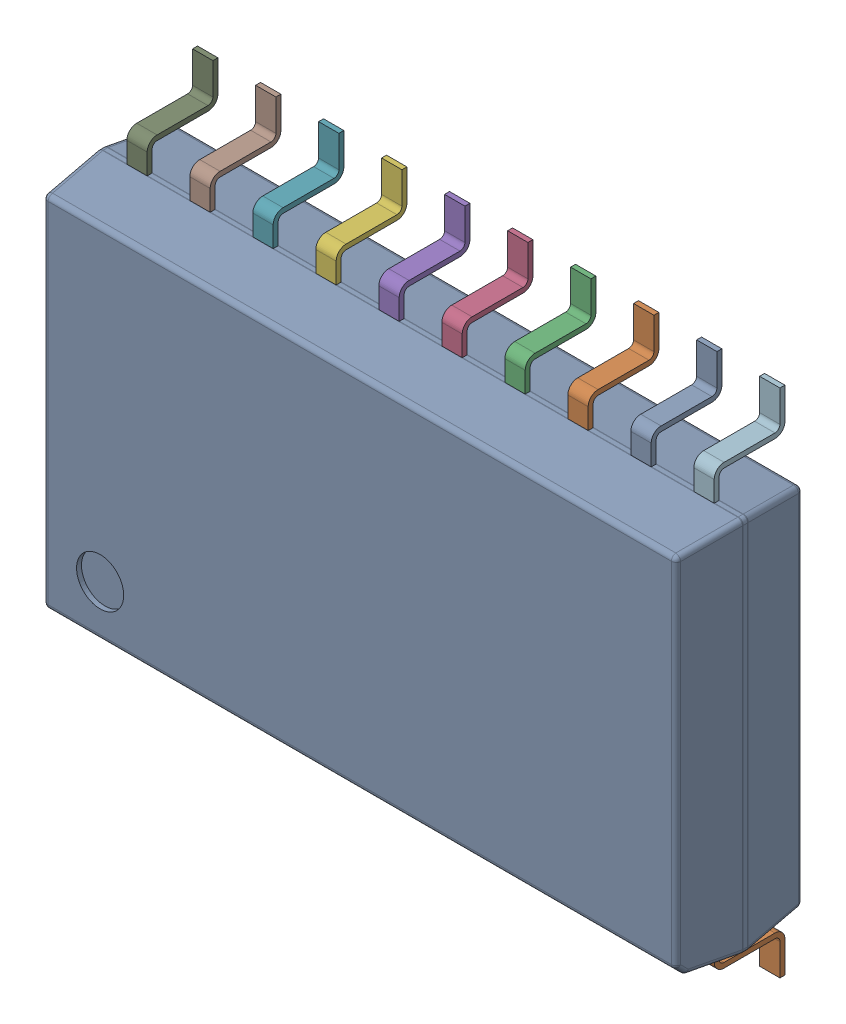
SolidWorks assembly U1, configuration Default. Lengths in mm.
Overall size (13.01 10.3 2.66).
24 component instances, 3 part files, 0 mates.
Components (placement in the parent):
- 809572592-1: 809572592 [Default] at (83.9483 50.292 0) x (0 1 0) z (0 0 1) size (10.3 13.01 2.66)
  - Open_CASCADE_STEP_translator_6.8_1.1-1: Open_CASCADE_STEP_translator_6.8_1.1 [Default] at (-3.8 -6.5 0.001) size (0.95 0.95 0)
  - Body_2-1: Body_2 [Default] at (-3.8 -6.5 0) size (7.61 13.01 2.56)
    - Open_CASCADE_STEP_translator_6.8_1.2.1-1: Open_CASCADE_STEP_translator_6.8_1.2.1 [Default] at origin size (7.61 13.01 2.56)
  - Leader-1: Leader [Default] at (-3.8 -5.715 0) x (-1 0 0) z (0 0 1) size (1.35 0.41 1.43)
  - Leader-2: Leader [Default] at (-3.8 -4.445 0) x (-1 0 0) z (0 0 1) size (1.35 0.41 1.43)
  - Leader-3: Leader [Default] at (-3.8 -3.175 0) x (-1 0 0) z (0 0 1) size (1.35 0.41 1.43)
  - Leader-4: Leader [Default] at (-3.8 -1.905 0) x (-1 0 0) z (0 0 1) size (1.35 0.41 1.43)
  - Leader-5: Leader [Default] at (-3.8 -0.635 0) x (-1 0 0) z (0 0 1) size (1.35 0.41 1.43)
  - Leader-6: Leader [Default] at (-3.8 0.635 0) x (-1 0 0) z (0 0 1) size (1.35 0.41 1.43)
  - Leader-7: Leader [Default] at (-3.8 1.905 0) x (-1 0 0) z (0 0 1) size (1.35 0.41 1.43)
  - Leader-8: Leader [Default] at (-3.8 3.175 0) x (-1 0 0) z (0 0 1) size (1.35 0.41 1.43)
  - Leader-9: Leader [Default] at (-3.8 4.445 0) x (-1 0 0) z (0 0 1) size (1.35 0.41 1.43)
  - Leader-10: Leader [Default] at (-3.8 5.715 0) x (-1 0 0) z (0 0 1) size (1.35 0.41 1.43)
  - Leader-11: Leader [Default] at (3.8 -5.715 0) size (1.35 0.41 1.43)
  - Leader-12: Leader [Default] at (3.8 -4.445 0) size (1.35 0.41 1.43)
  - Leader-13: Leader [Default] at (3.8 -3.175 0) size (1.35 0.41 1.43)
  - Leader-14: Leader [Default] at (3.8 -1.905 0) size (1.35 0.41 1.43)
  - Leader-15: Leader [Default] at (3.8 -0.635 0) size (1.35 0.41 1.43)
  - Leader-16: Leader [Default] at (3.8 0.635 0) size (1.35 0.41 1.43)
  - Leader-17: Leader [Default] at (3.8 1.905 0) size (1.35 0.41 1.43)
  - Leader-18: Leader [Default] at (3.8 3.175 0) size (1.35 0.41 1.43)
  - Leader-19: Leader [Default] at (3.8 4.445 0) size (1.35 0.41 1.43)
  - Leader-20: Leader [Default] at (3.8 5.715 0) size (1.35 0.41 1.43)
